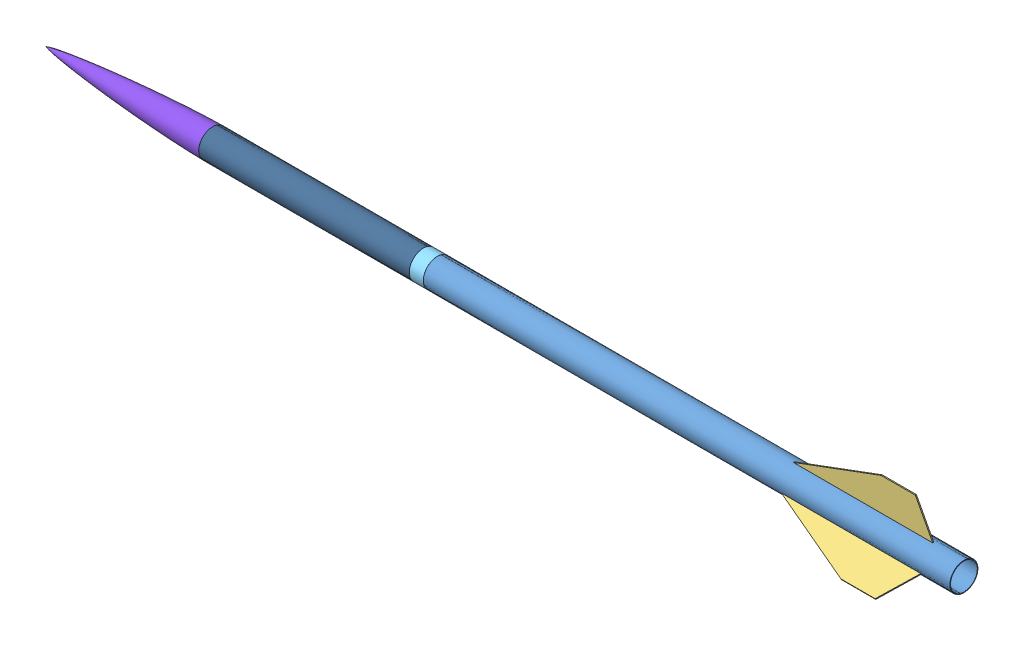
SolidWorks assembly GoDevilStandard, configuration Default. Lengths in mm.
Overall size (1328.42 102.03 117.81).
16 component instances, 10 part files, 6 mates.
Components (placement in the parent):
- MotorMount-1: MotorMount [Default] at (-343.5505 -5.6552 -27.1634) size (762 102.03 117.81)
  - 30InThinWallFiberglass-1: 30InThinWallFiberglass [Default] at origin size (762 40.74 40.74)
  - InteriorMotorRetainer-1: InteriorMotorRetainer [Default] at (127 0 0) size (33.19 40.62 40.11)
  - Fin-1: Fin [Default] at (515.9375 20.3708 -0.7874) size (201.61 47.19 1.57)
  - Fin-2: Fin [Default] at (515.9375 -9.5035 18.0353) x (1 0 0) z (0 -0.866025 -0.5) size (201.61 47.19 1.57)
  - Fin-3: Fin [Default] at (515.9375 -10.8673 -17.2479) x (1 0 0) z (0 0.866025 -0.5) size (201.61 47.19 1.57)
- ElectronicsBay-1: ElectronicsBay [Default] at (-393.5659 -0.2825 -9.7824) size (157.23 50.58 50.58)
  - 6inFiberglassCoupler-1: 6inFiberglassCoupler [Default] at (-36.3446 -5.3728 -17.381) size (152.4 38.76 38.76)
  - 08InThinWallFiberglass-1: 08InThinWallFiberglass [Default] at (29.6954 -5.3728 -17.381) size (20.32 40.74 40.74)
  - EBayBulkhead-1: EBayBulkhead [Default] at (-38.7576 -5.3728 -17.381) size (5.08 38.66 38.66)
  - EBayBulkhead-2: EBayBulkhead [Default] at (118.4684 -5.3728 -17.381) x (-1 0 0) z (0 -0.385815 -0.922576) size (5.08 38.66 38.66)
- NoseCone-1: NoseCone [Default] at (-678.8092 -6.1774 -10.304) x (1 0 0) z (0 0.190904 0.981609) size (296.37 40.64 40.64)
  - 3inFiberglassCoupler-1: 3inFiberglassCoupler [Default] at (-12.4673 3.7311 -16.4496) size (77.67 38.76 38.76)
  - VonKarmanNoseCone-1: VonKarmanNoseCone [Default] at (-231.1613 3.7311 -16.4496) size (241.3 40.64 40.64)
  - NoseConeBulkhead-1: NoseConeBulkhead [Default] at (59.6179 3.7311 -16.4496) size (2.41 34.67 34.67)
- 12InThinWallFiberglass-1: 12InThinWallFiberglass [Default] at (-668.6705 -5.6552 -27.1634) x (1 0 0) z (0 0.043037 0.999073) size (304.8 40.74 40.74)
Mates (geometry in assembly coordinates):
- Concentric1: concentric aligned: cylinder of MotorMount-1/30InThinWallFiberglass-1 through (418.4495 -5.6552 -27.1634) axis (-1 0 0) radius 19.4818; cylinder of ElectronicsBay-1/6inFiberglassCoupler-1 through (-277.5105 -5.6552 -27.1634) axis (-1 0 0) radius 19.3802
- Coincident1: coincident anti-aligned: plane of MotorMount-1/30InThinWallFiberglass-1 through (-343.5505 -5.6552 -27.1634) normal (-1 0 0); plane of ElectronicsBay-1/08InThinWallFiberglass-1 through (-343.5505 -5.6552 -27.1634) normal (1 0 0)
- Concentric2: concentric aligned: cylinder of ElectronicsBay-1/6inFiberglassCoupler-1 through (-277.5105 -5.6552 -27.1634) axis (-1 0 0) radius 19.3802; cylinder of 12InThinWallFiberglass-1 through (-363.8705 -5.6552 -27.1634) axis (-1 0 0) radius 19.4818
- Concentric3: concentric aligned: cylinder of NoseCone-1/3inFiberglassCoupler-1 through (-613.6033 -5.6552 -27.1634) axis (-1 0 0) radius 19.3802; cylinder of 12InThinWallFiberglass-1 through (-363.8705 -5.6552 -27.1634) axis (-1 0 0) radius 19.4818
- Coincident2: coincident anti-aligned: plane of ElectronicsBay-1/08InThinWallFiberglass-1 through (-363.8705 -5.6552 -27.1634) normal (-1 0 0); plane of 12InThinWallFiberglass-1 through (-363.8705 -5.6552 -27.1634) normal (1 0 0)
- Coincident3: coincident anti-aligned: plane of NoseCone-1/VonKarmanNoseCone-1 through (-668.6705 -5.6552 -27.1634) normal (1 0 0); plane of 12InThinWallFiberglass-1 through (-668.6705 -5.6552 -27.1634) normal (-1 0 0)
